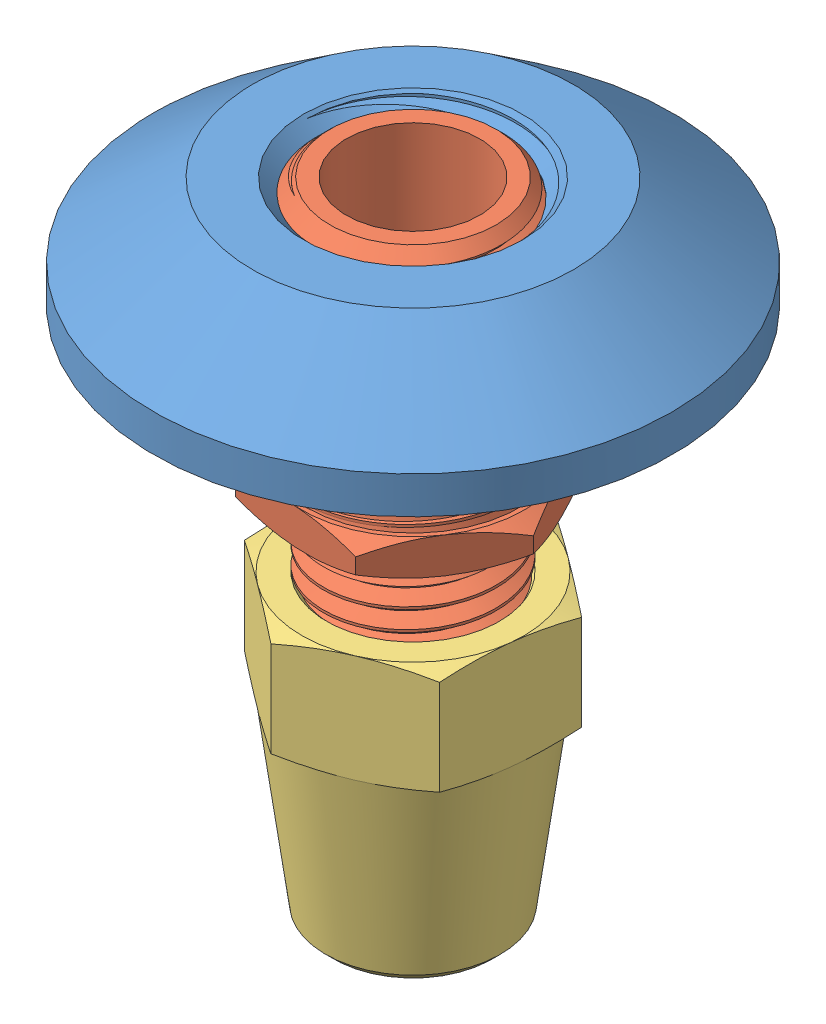
SolidWorks assembly Assem3, configuration Default. Lengths in mm.
Overall size (33.35 41.42 33.35).
3 component instances, 3 part files, 4 mates.
Components (placement in the parent):
- 8694T420_WELD-ON FITTING FOR FLAT TANKS-1: 8694T420_WELD-ON FITTING FOR FLAT TANKS [8694T42] at (-12.1242 -10.6093 12.2709) size (33.35 10.96 33.35)
- 50635K374_45 DEG FLARED FITTING FOR COPPER BRASS TUBING-2: 50635K374_45 DEG FLARED FITTING FOR COPPER BRASS TUBING [50635K374] at (-12.1242 -19.0929 12.2709) x (0 -1 0) z (0.834803 0 0.550549) size (31.64 16.5 14.3)
- 50635K562_45 DEG FLARED FITTING FOR COPPER BRASS TUBING-1: 50635K562_45 DEG FLARED FITTING FOR COPPER BRASS TUBING [50635K562] at (-12.1242 -25.448 12.2709) x (0 -1 0) z (0.397401 0 0.917645) size (19.58 16.5 14.29)
Mates (geometry in assembly coordinates):
- Concentric1: concentric: circle of 8694T420_WELD-ON FITTING FOR FLAT TANKS-1; circle of 50635K374_45 DEG FLARED FITTING FOR COPPER BRASS TUBING-2
- Coincident2: coincident aligned: plane of 8694T420_WELD-ON FITTING FOR FLAT TANKS-1 through (-12.1242 -3.4719 12.2709) normal (0 1 0); plane of 50635K374_45 DEG FLARED FITTING FOR COPPER BRASS TUBING-2 through (-12.1242 -3.4719 12.2709) normal (0 1 0)
- Concentric2: concentric: cylinder of 50635K374_45 DEG FLARED FITTING FOR COPPER BRASS TUBING-2 through (-12.1242 -3.4719 12.2709) axis (0 1 0) radius 4.6044; circle of 50635K562_45 DEG FLARED FITTING FOR COPPER BRASS TUBING-1
- Coincident3: coincident anti-aligned: cone of 50635K374_45 DEG FLARED FITTING FOR COPPER BRASS TUBING-2 through (-12.1242 -32.7499 12.2709) axis (0 -1 0); circle of 50635K562_45 DEG FLARED FITTING FOR COPPER BRASS TUBING-1
